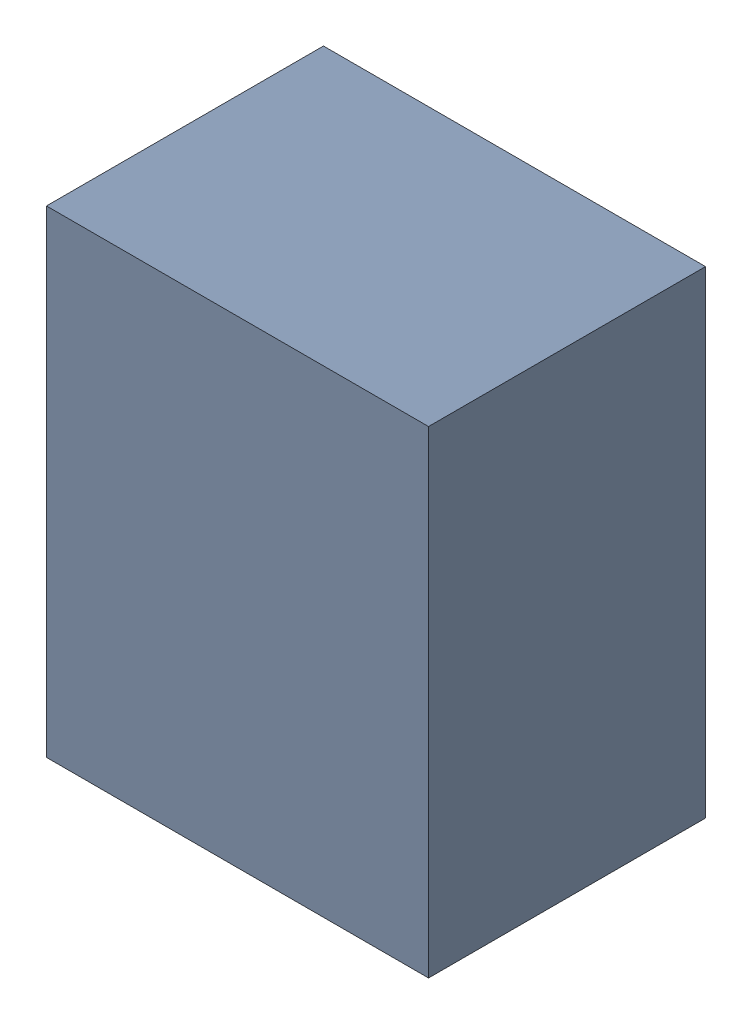
SolidWorks assembly U14, configuration Default. Lengths in mm.
Overall size (0.8 1 0.58).
2 component instances, 1 part files, 0 mates.
Components (placement in the parent):
- 836751984-1: 836751984 [Default] at (133.05 52.5 0.5) size (0.8 1 0.58)
  - Extruded_32-1: Extruded_32 [Default] at origin size (0.8 1 0.58)
